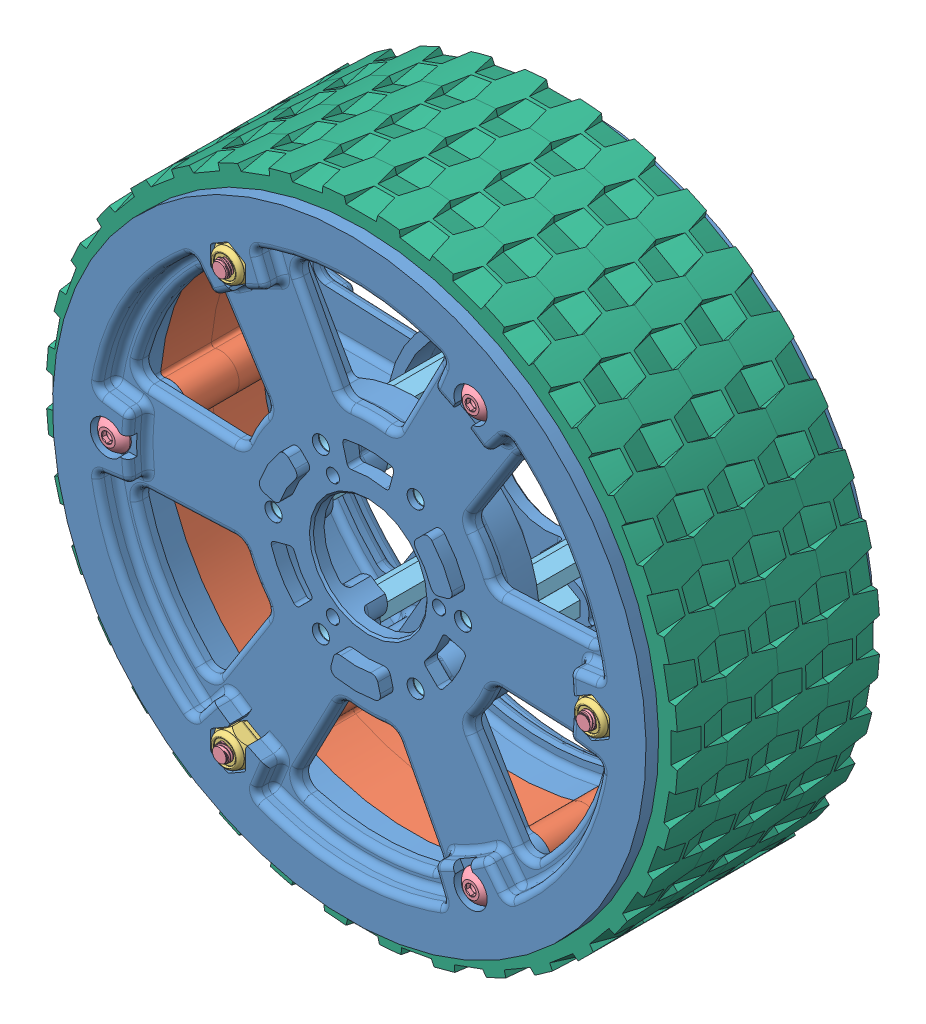
SolidWorks assembly 217-2860-on-wheel-STEP 1in, configuration Default. Lengths in mm.
Overall size (203.85 203.85 61.62).
34 component instances, 7 part files, 0 mates.
Components (placement in the parent):
- 217-2589-001 Rev3-1: 217-2589-001 Rev3 [Default] at (-6.6039 5.1658 6.3657) size (149.22 149.22 19.81)
- 217-2589-003 Rev1-1: 217-2589-003 Rev1 [Default] at (-6.6039 5.1658 12.7157) x (0 0 -1) z (0.173648 0.984808 0) size (20.32 144.53 143.68)
- 217-2589-001 Rev3-2: 217-2589-001 Rev3 [Default] at (-6.6039 5.1658 31.7657) x (0.5 -0.866025 0) z (0 0 -1) size (149.22 149.22 19.81)
- NUT-832-NYLOCK-1: NUT-832-NYLOCK [Default] at (-67.5639 5.1658 -5.7031) x (0.866025 -0.5 0) z (0.5 0.866025 0) size (10.2 5.86 8.12)
- 832-2250_91255A206-1: 832-2250_91255A206 [Default] at (-67.5639 5.1658 45.4182) x (0.994604 -0.103745 0) z (0 0 1) size (7.98 8.02 59.89)
- 217-2589-003 Rev1-2: 217-2589-003 Rev1 [Default] at (-6.6039 5.1658 25.4157) x (0 0 -1) z (0.173648 0.984808 0) size (20.32 144.53 143.68)
- 832-2250_91255A206-2: 832-2250_91255A206 [Default] at (-37.0839 -47.6271 -7.2868) x (0.359425 0.933174 0) z (0 0 -1) size (7.98 8.02 59.89)
- NUT-832-NYLOCK-2: NUT-832-NYLOCK [Default] at (-37.0839 -47.6271 43.8346) x (0 -1 0) z (-1 0 0) size (10.2 5.86 8.12)
- NUT-832-NYLOCK-3: NUT-832-NYLOCK [Default] at (-37.0839 57.9587 43.8346) x (-0.866025 0.5 0) z (0.5 0.866025 0) size (10.2 5.86 8.12)
- NUT-832-NYLOCK-4: NUT-832-NYLOCK [Default] at (54.3561 5.1658 43.8346) x (0.866025 0.5 0) z (0.5 -0.866025 0) size (10.2 5.86 8.12)
- NUT-832-NYLOCK-5: NUT-832-NYLOCK [Default] at (23.8761 57.9587 -5.7031) x (-0.866025 -0.5 0) z (0.5 -0.866025 0) size (10.2 5.86 8.12)
- NUT-832-NYLOCK-6: NUT-832-NYLOCK [Default] at (23.8761 -47.6271 -5.7031) x (0 1 0) z (-1 0 0) size (10.2 5.86 8.12)
- 832-2250_91255A206-3: 832-2250_91255A206 [Default] at (23.8761 57.9587 45.4182) x (-0.587147 -0.80948 0) z (0 0 1) size (7.98 8.02 59.89)
- 832-2250_91255A206-4: 832-2250_91255A206 [Default] at (23.8761 -47.6271 45.4182) x (-0.407457 0.913225 0) z (0 0 1) size (7.98 8.02 59.89)
- 832-2250_91255A206-5: 832-2250_91255A206 [Default] at (-37.0839 57.9587 -7.2868) x (0.62844 -0.777858 0) z (0 0 -1) size (7.98 8.02 59.89)
- 832-2250_91255A206-6: 832-2250_91255A206 [Default] at (54.3561 5.1658 -7.2868) x (-0.987865 -0.155316 0) z (0 0 -1) size (7.98 8.02 59.89)
- 217-2588-005 Rev1-1: 217-2588-005 Rev1 [Default] at (-18.5101 25.788 19.1292) x (0 1 0) z (1 0 0) size (7.34 45.33 7.34)
- 217-2588-005 Rev1-2: 217-2588-005 Rev1 [Default] at (5.3024 25.788 19.1292) x (0.866025 0.5 0) z (0.5 -0.866025 0) size (7.34 45.33 7.34)
- 217-2588-005 Rev1-3: 217-2588-005 Rev1 [Default] at (17.2086 5.1658 19.1292) x (0.866025 -0.5 0) z (-0.5 -0.866025 0) size (7.34 45.33 7.34)
- 217-2588-005 Rev1-4: 217-2588-005 Rev1 [Default] at (5.3024 -15.4564 19.1292) x (0 -1 0) z (-1 0 0) size (7.34 45.33 7.34)
- 217-2588-005 Rev1-5: 217-2588-005 Rev1 [Default] at (-18.5101 -15.4564 19.1292) x (-0.866025 -0.5 0) z (-0.5 0.866025 0) size (7.34 45.33 7.34)
- 217-2588-005 Rev1-6: 217-2588-005 Rev1 [Default] at (-30.4164 5.1658 19.1292) x (-0.866025 0.5 0) z (0.5 0.866025 0) size (7.34 45.33 7.34)
- 217-2860-000 Rev2-1: 217-2860-000 Rev2 [Default] at (-6.6039 5.1658 0.0157) x (0.999997 0.002561 0) z (0 0 1) size (158.75 158.75 12.71)
  - 217-2860-001 Rev3-1: 217-2860-001 Rev3 [Default] at origin size (158.75 158.75 12.71)
  - 217-2860-011 Rev1-1: 217-2860-011 Rev1 [Default] at origin size (146.53 146.53 8.05)
- 217-2860-000 Rev2-2: 217-2860-000 Rev2 [Default] at (-6.6039 5.1658 12.7157) x (0.999997 0.002561 0) z (0 0 1) size (158.75 158.75 12.71)
  - 217-2860-001 Rev3-1: 217-2860-001 Rev3 [Default] at origin size (158.75 158.75 12.71)
  - 217-2860-011 Rev1-1: 217-2860-011 Rev1 [Default] at origin size (146.53 146.53 8.05)
- 217-2860-000 Rev2-3: 217-2860-000 Rev2 [Default] at (-6.6039 5.1658 25.4157) x (0.999997 0.002561 0) z (0 0 1) size (158.75 158.75 12.71)
  - 217-2860-001 Rev3-1: 217-2860-001 Rev3 [Default] at origin size (158.75 158.75 12.71)
  - 217-2860-011 Rev1-1: 217-2860-011 Rev1 [Default] at origin size (146.53 146.53 8.05)
- 217-2860-000 Rev2-4: 217-2860-000 Rev2 [Default] at (-6.6039 5.1658 38.1157) x (0.999997 0.002561 0) z (0 0 1) size (158.75 158.75 12.71)
  - 217-2860-001 Rev3-1: 217-2860-001 Rev3 [Default] at origin size (158.75 158.75 12.71)
  - 217-2860-011 Rev1-1: 217-2860-011 Rev1 [Default] at origin size (146.53 146.53 8.05)
